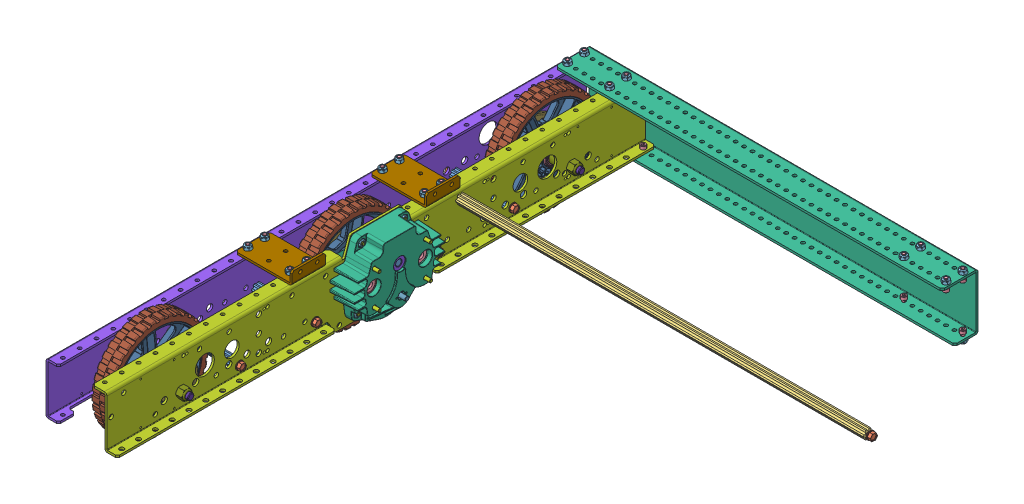
SolidWorks assembly AM14U3 Long Half, configuration Default. Lengths in mm.
Overall size (722.96 212.37 816.74).
154 component instances, 35 part files, 29 mates.
Components (placement in the parent):
- AM14U3 Long Frame Half-1: AM14U3 Long Frame Half [Default] at (0 136.1443 -762.762) size (722.38 116.33 816.74)
  - 500 Churro 3.375 in-1: 500 Churro 3.375 in [Default] at (-501.65 -66.929 448.437) x (0 0 1) z (-1 0 0) size (14.66 12.7 85.72)
  - 500 Churro 3.375 in-2: 500 Churro 3.375 in [Default] at (-501.65 -66.929 562.737) x (0 0 1) z (-1 0 0) size (14.66 12.7 85.72)
  - 500 Churro 3.375 in-3: 500 Churro 3.375 in [Default] at (-501.65 -66.929 264.287) x (0 0 1) z (-1 0 0) size (14.66 12.7 85.72)
  - 500 Churro 3.375 in-4: 500 Churro 3.375 in [Default] at (-501.65 -66.929 149.987) x (0 0 1) z (-1 0 0) size (14.66 12.7 85.72)
  - 0.25-20 x 0.75 in Thread Rolling Screw-1: 0.25-20 x 0.75 in Thread Rolling Screw [FHTS 0.25-20-G-0.75-C] at (-498.475 -66.929 562.737) x (-1 0 0) z (0 0.924225 0.381849) size (24.64 12.19 12.19)
  - 0.25-20 x 0.75 in Thread Rolling Screw-2: 0.25-20 x 0.75 in Thread Rolling Screw [FHTS 0.25-20-G-0.75-C] at (-498.475 -66.929 448.437) x (-1 0 0) z (0 0.924225 0.381849) size (24.64 12.19 12.19)
  - 0.25-20 x 0.75 in Thread Rolling Screw-3: 0.25-20 x 0.75 in Thread Rolling Screw [FHTS 0.25-20-G-0.75-C] at (-498.475 -66.929 264.287) x (-1 0 0) z (0 0.924225 0.381849) size (24.64 12.19 12.19)
  - 0.25-20 x 0.75 in Thread Rolling Screw-4: 0.25-20 x 0.75 in Thread Rolling Screw [FHTS 0.25-20-G-0.75-C] at (-498.475 -66.929 149.987) x (-1 0 0) z (0 0.924225 0.381849) size (24.64 12.19 12.19)
  - 0.25-20 x 0.75 in Thread Rolling Screw-5: 0.25-20 x 0.75 in Thread Rolling Screw [FHTS 0.25-20-G-0.75-C] at (-590.55 -66.929 562.737) size (24.64 12.19 12.19)
  - 0.25-20 x 0.75 in Thread Rolling Screw-6: 0.25-20 x 0.75 in Thread Rolling Screw [FHTS 0.25-20-G-0.75-C] at (-590.55 -66.929 448.437) size (24.64 12.19 12.19)
  - 0.25-20 x 0.75 in Thread Rolling Screw-7: 0.25-20 x 0.75 in Thread Rolling Screw [FHTS 0.25-20-G-0.75-C] at (-590.55 -66.929 149.987) size (24.64 12.19 12.19)
  - 0.25-20 x 0.75 in Thread Rolling Screw-8: 0.25-20 x 0.75 in Thread Rolling Screw [FHTS 0.25-20-G-0.75-C] at (-590.55 -66.929 264.287) size (24.64 12.19 12.19)
  - 0.25-20 x 0.75 in Thread Rolling Screw-9: 0.25-20 x 0.75 in Thread Rolling Screw [FHTS 0.25-20-G-0.75-C] at (-501.65 -15.494 229.362) size (24.64 12.19 12.19)
  - 0.25-20 x 0.75 in Thread Rolling Screw-10: 0.25-20 x 0.75 in Thread Rolling Screw [FHTS 0.25-20-G-0.75-C] at (120.65 -15.494 229.362) x (-1 0 0) z (0 -0.924225 -0.381849) size (24.64 12.19 12.19)
  - 500 Churro 24.25 in-1: 500 Churro 24.25 in [Default] at (117.475 -15.494 229.362) x (0 0 1) z (-1 0 0) size (14.66 12.7 615.95)
  - 10-32 x 0.5 in SHCS Screw-27: 10-32 x 0.5 in SHCS Screw [HX-SHCS 0.19-32x1.375x1-C] at (-577.85 -11.43 -11.938) x (0 1 0) z (0 0 1) size (17.53 7.94 7.94)
  - 10-32 x 0.5 in SHCS Screw-28: 10-32 x 0.5 in SHCS Screw [HX-SHCS 0.19-32x1.375x1-C] at (-577.85 -11.43 -37.338) x (0 1 0) z (0 0 1) size (17.53 7.94 7.94)
  - 10-32 x 0.5 in SHCS Screw-29: 10-32 x 0.5 in SHCS Screw [HX-SHCS 0.19-32x1.375x1-C] at (-514.35 -11.43 -37.338) x (0 1 0) z (0 0 1) size (17.53 7.94 7.94)
  - 10-32 x 0.5 in SHCS Screw-30: 10-32 x 0.5 in SHCS Screw [HX-SHCS 0.19-32x1.375x1-C] at (-514.35 -11.43 -11.938) x (0 1 0) z (0 0 1) size (17.53 7.94 7.94)
  - 10-32 x 0.5 in SHCS Screw-31: 10-32 x 0.5 in SHCS Screw [HX-SHCS 0.19-32x1.375x1-C] at (-488.95 -73.152 -37.338) x (0 -1 0) z (0 0 1) size (17.53 7.94 7.94)
  - 10-32 x 0.5 in SHCS Screw-32: 10-32 x 0.5 in SHCS Screw [HX-SHCS 0.19-32x1.375x1-C] at (-577.85 -73.152 -37.338) x (0 -1 0) z (0 0 1) size (17.53 7.94 7.94)
  - 10-32 x 0.5 in SHCS Screw-40: 10-32 x 0.5 in SHCS Screw [HX-SHCS 0.19-32x1.375x1-C] at (-6.35 -11.176 -11.938) x (0 1 0) z (-0.991845 0 0.127447) size (17.53 7.94 7.94)
  - 10-32 x 0.5 in SHCS Screw-41: 10-32 x 0.5 in SHCS Screw [HX-SHCS 0.19-32x1.375x1-C] at (-6.35 -11.176 -37.338) x (0 1 0) z (0.595464 0 0.803382) size (17.53 7.94 7.94)
  - 10-32 x 0.5 in SHCS Screw-42: 10-32 x 0.5 in SHCS Screw [HX-SHCS 0.19-32x1.375x1-C] at (-69.85 -11.176 -11.938) x (0 1 0) z (0.578861 0 0.815426) size (17.53 7.94 7.94)
  - 10-32 x 0.5 in SHCS Screw-43: 10-32 x 0.5 in SHCS Screw [HX-SHCS 0.19-32x1.375x1-C] at (-69.85 -11.176 -37.338) x (0 1 0) z (0.958905 0 0.283727) size (17.53 7.94 7.94)
  - 10-32 x 0.5 in SHCS Screw-44: 10-32 x 0.5 in SHCS Screw [HX-SHCS 0.19-32x1.375x1-C] at (-6.35 -73.406 -37.338) x (0 -1 0) z (-0.989362 0 -0.145473) size (17.53 7.94 7.94)
  - 10-32 x 0.5 in SHCS Screw-45: 10-32 x 0.5 in SHCS Screw [HX-SHCS 0.19-32x1.375x1-C] at (-95.25 -73.406 -37.338) x (0 -1 0) z (-0.875347 0 0.483496) size (17.53 7.94 7.94)
  - 10-32 Nylock Nut-27: 10-32 Nylock Nut [Default] at (-69.85 0 -11.938) x (1 0 0) z (0 1 0) size (10.18 11.01 7.1)
  - 10-32 Nylock Nut-28: 10-32 Nylock Nut [Default] at (-69.85 0 -37.338) x (1 0 0) z (0 1 0) size (10.18 11.01 7.1)
  - 10-32 Nylock Nut-29: 10-32 Nylock Nut [Default] at (-6.35 0 -37.338) x (1 0 0) z (0 1 0) size (10.18 11.01 7.1)
  - 10-32 Nylock Nut-30: 10-32 Nylock Nut [Default] at (-6.35 0 -11.938) x (1 0 0) z (0 1 0) size (10.18 11.01 7.1)
  - 10-32 Nylock Nut-31: 10-32 Nylock Nut [Default] at (-6.35 -84.582 -37.338) x (1 0 0) z (0 -1 0) size (10.18 11.01 7.1)
  - 10-32 Nylock Nut-32: 10-32 Nylock Nut [Default] at (-95.25 -84.582 -37.338) x (1 0 0) z (0 -1 0) size (10.18 11.01 7.1)
  - 10-32 Nylock Nut-33: 10-32 Nylock Nut [Default] at (-514.35 0 -11.938) x (1 0 0) z (0 1 0) size (10.18 11.01 7.1)
  - 10-32 Nylock Nut-34: 10-32 Nylock Nut [Default] at (-514.35 0 -37.338) x (1 0 0) z (0 1 0) size (10.18 11.01 7.1)
  - 10-32 Nylock Nut-35: 10-32 Nylock Nut [Default] at (-577.85 0 -37.338) x (1 0 0) z (0 1 0) size (10.18 11.01 7.1)
  - 10-32 Nylock Nut-36: 10-32 Nylock Nut [Default] at (-577.85 0 -11.938) x (1 0 0) z (0 1 0) size (10.18 11.01 7.1)
  - 10-32 Nylock Nut-37: 10-32 Nylock Nut [Default] at (-488.95 -84.582 -37.338) x (1 0 0) z (0 -1 0) size (10.18 11.01 7.1)
  - 10-32 Nylock Nut-38: 10-32 Nylock Nut [Default] at (-577.85 -84.582 -37.338) x (1 0 0) z (0 -1 0) size (10.18 11.01 7.1)
  - 10-32 x 0.5 in SHCS Screw-46: 10-32 x 0.5 in SHCS Screw [HX-SHCS 0.19-32x1.375x1-C] at (-577.85 -11.43 445.262) x (0 1 0) z (0 0 1) size (17.53 7.94 7.94)
  - 10-32 x 0.5 in SHCS Screw-47: 10-32 x 0.5 in SHCS Screw [HX-SHCS 0.19-32x1.375x1-C] at (-577.85 -11.43 470.662) x (0 1 0) z (0 0 1) size (17.53 7.94 7.94)
  - 10-32 x 0.5 in SHCS Screw-48: 10-32 x 0.5 in SHCS Screw [HX-SHCS 0.19-32x1.375x1-C] at (-514.35 -11.43 445.262) x (0 1 0) z (0 0 1) size (17.53 7.94 7.94)
  - 10-32 x 0.5 in SHCS Screw-49: 10-32 x 0.5 in SHCS Screw [HX-SHCS 0.19-32x1.375x1-C] at (-514.35 -11.43 470.662) x (0 1 0) z (0 0 1) size (17.53 7.94 7.94)
  - 10-32 x 0.5 in SHCS Screw-50: 10-32 x 0.5 in SHCS Screw [HX-SHCS 0.19-32x1.375x1-C] at (-577.85 -11.43 267.462) x (0 1 0) z (0 0 1) size (17.53 7.94 7.94)
  - 10-32 x 0.5 in SHCS Screw-51: 10-32 x 0.5 in SHCS Screw [HX-SHCS 0.19-32x1.375x1-C] at (-577.85 -11.43 242.062) x (0 1 0) z (0 0 1) size (17.53 7.94 7.94)
  - 10-32 x 0.5 in SHCS Screw-52: 10-32 x 0.5 in SHCS Screw [HX-SHCS 0.19-32x1.375x1-C] at (-514.35 -11.43 242.062) x (0 1 0) z (0 0 1) size (17.53 7.94 7.94)
  - 10-32 x 0.5 in SHCS Screw-53: 10-32 x 0.5 in SHCS Screw [HX-SHCS 0.19-32x1.375x1-C] at (-514.35 -11.43 267.462) x (0 1 0) z (0 0 1) size (17.53 7.94 7.94)
  - 10-32 Nylock Nut-39: 10-32 Nylock Nut [Default] at (-514.35 -0.254 267.462) x (1 0 0) z (0 1 0) size (10.18 11.01 7.1)
  - 10-32 Nylock Nut-40: 10-32 Nylock Nut [Default] at (-514.35 -0.254 242.062) x (1 0 0) z (0 1 0) size (10.18 11.01 7.1)
  - 10-32 Nylock Nut-41: 10-32 Nylock Nut [Default] at (-577.85 -0.254 267.462) x (1 0 0) z (0 1 0) size (10.18 11.01 7.1)
  - 10-32 Nylock Nut-42: 10-32 Nylock Nut [Default] at (-577.85 -0.254 242.062) x (1 0 0) z (0 1 0) size (10.18 11.01 7.1)
  - 10-32 Nylock Nut-43: 10-32 Nylock Nut [Default] at (-514.35 -0.254 470.662) x (1 0 0) z (0 1 0) size (10.18 11.01 7.1)
  - 10-32 Nylock Nut-44: 10-32 Nylock Nut [Default] at (-577.85 -0.254 470.662) x (1 0 0) z (0 1 0) size (10.18 11.01 7.1)
  - 10-32 Nylock Nut-45: 10-32 Nylock Nut [Default] at (-577.85 -0.254 445.262) x (1 0 0) z (0 1 0) size (10.18 11.01 7.1)
  - 10-32 Nylock Nut-46: 10-32 Nylock Nut [Default] at (-514.35 -0.254 445.262) x (1 0 0) z (0 1 0) size (10.18 11.01 7.1)
  - AM14U3 End Plate_Long-1: AM14U3 End Plate_Long [Default] at (-488.098 60.9785 -76.8664) x (1 0 0) z (0 -1 0) size (584.2 53.97 84.58)
  - AM14U3 Inner Plate-1: AM14U3 Inner Plate [Default] at (-501.65 -77.216 762.762) x (0 0 -1) z (0 -1 0) size (812.8 38.1 116.33)
  - AM14U3 Outer Plate-1: AM14U3 Outer Plate [DefaultSM-FLAT-PATTERN] at (-587.375 -77.216 -50.038) x (0 0 1) z (0 -1 0) size (812.8 19.05 77.72)
  - Bracket 2x3 Hole Pattern-1: Bracket 2x3 Hole Pattern [Default] at (-584.2 -3.429 496.062) size (85.72 19.05 50.8)
  - Bracket 2x3 Hole Pattern-2: Bracket 2x3 Hole Pattern [Default] at (-584.2 -3.429 292.862) size (85.72 19.05 50.8)
- Wheel HiGrip 6 in - Bearings, Pulleys, Spacers-1: Wheel HiGrip 6 in - Bearings, Pulleys, Spacers [Default] at (-576.1365 93.2036 -263.8267) x (1 0 0) z (0 -0.576171 0.817329) size (85.56 152.4 152.4)
  - Wheel HiGrip 6 in-1: Wheel HiGrip 6 in [Default] at (83.7987 67.439 110.9939) size (35.05 152.4 152.4)
    - Wheel HiGrip 6 in_Wheel-1: Wheel HiGrip 6 in_Wheel [Default] at (-52.6446 9.4231 21.378) size (35.05 132.08 132.08)
    - Wheel HiGrip 6 in_Tread-1: Wheel HiGrip 6 in_Tread [Default] at (-65.3446 9.4231 21.378) x (0 0 -1) z (1 0 0) size (152.4 152.4 25.58)
  - Half Pulley 42t 5 mm HTD-1: Half Pulley 42t 5 mm HTD [Default] at (47.6006 76.862 132.3719) x (1 0 0) z (0 -0.5 0.866025) size (13 74.23 74.23)
  - Half Pulley 42t 5 mm HTD-2: Half Pulley 42t 5 mm HTD [Default] at (64.263 76.862 132.3719) x (-1 0 0) z (0 -0.499927 0.866067) size (13 74.23 74.23)
  - Bearing 1614ZZ-1: Bearing 1614ZZ [Default] at (62.612 76.862 132.3719) x (0 -0.157148 -0.987575) z (-1 0 0) size (28.57 28.57 9.53)
  - Bearing 1614ZZ-2: Bearing 1614ZZ [Default] at (15.2791 76.862 132.3719) x (0 0 -1) z (1 0 0) size (28.57 28.57 9.53)
  - 10-24 x 1.25 in Thread Forming Screw-1: 10-24 x 1.25 in Thread Forming Screw [93882A213] at (63.247 76.8605 108.5602) x (0 0 -1) z (1 0 0) size (10.52 10.52 35.59)
  - 10-24 x 1.25 in Thread Forming Screw-2: 10-24 x 1.25 in Thread Forming Screw [93882A213] at (63.247 97.4833 120.4656) x (0 0 -1) z (1 0 0) size (10.52 10.52 35.59)
  - 10-24 x 1.25 in Thread Forming Screw-3: 10-24 x 1.25 in Thread Forming Screw [93882A213] at (63.247 56.2398 144.2799) x (0 0 -1) z (1 0 0) size (10.52 10.52 35.59)
  - 10-24 x 1.25 in Thread Forming Screw-4: 10-24 x 1.25 in Thread Forming Screw [93882A213] at (63.247 76.8625 156.1852) x (0 -0.95788 -0.287168) z (1 0 0) size (10.52 10.52 35.59)
  - 10-24 x 1.25 in Thread Forming Screw-5: 10-24 x 1.25 in Thread Forming Screw [93882A213] at (63.247 97.4843 144.2781) x (0 -0.868976 0.494854) z (1 0 0) size (10.52 10.52 35.59)
  - 10-24 x 1.25 in Thread Forming Screw-6: 10-24 x 1.25 in Thread Forming Screw [93882A213] at (63.247 56.2388 120.4674) x (0 -0.977348 -0.211637) z (1 0 0) size (10.52 10.52 35.59)
  - Spacer 0.28 in x 0.382 ID-1: Spacer 0.28 in x 0.382 ID [Default] at (74.4865 76.862 132.3719) x (0 -0.35357 0.935408) z (-1 0 0) size (13.16 13.16 7.11)
  - Spacer 0.85 in x 0.38 ID-1: Spacer 0.85 in x 0.38 ID [Default] at (-11.0734 76.862 132.3719) x (0 0 -1) z (1 0 0) size (19.05 19.05 21.59)
- Wheel HiGrip 6 in - Bearings, Pulleys, Spacers-2: Wheel HiGrip 6 in - Bearings, Pulleys, Spacers [Default] at (-512.7234 172.7479 -579.8665) x (-1 0 0) z (0 -0.924225 -0.381849) size (85.56 152.4 152.4)
  - Wheel HiGrip 6 in-1: Wheel HiGrip 6 in [Default] at (83.7987 67.439 110.9939) size (35.05 152.4 152.4)
    - Wheel HiGrip 6 in_Wheel-1: Wheel HiGrip 6 in_Wheel [Default] at (-52.6446 9.4231 21.378) size (35.05 132.08 132.08)
    - Wheel HiGrip 6 in_Tread-1: Wheel HiGrip 6 in_Tread [Default] at (-65.3446 9.4231 21.378) x (0 0 -1) z (1 0 0) size (152.4 152.4 25.58)
  - Half Pulley 42t 5 mm HTD-1: Half Pulley 42t 5 mm HTD [Default] at (47.6006 76.862 132.3719) x (1 0 0) z (0 -0.5 0.866025) size (13 74.23 74.23)
  - Half Pulley 42t 5 mm HTD-2: Half Pulley 42t 5 mm HTD [Default] at (64.263 76.862 132.3719) x (-1 0 0) z (0 -0.499927 0.866067) size (13 74.23 74.23)
  - Bearing 1614ZZ-1: Bearing 1614ZZ [Default] at (62.612 76.862 132.3719) x (0 -0.157148 -0.987575) z (-1 0 0) size (28.57 28.57 9.53)
  - Bearing 1614ZZ-2: Bearing 1614ZZ [Default] at (15.2791 76.862 132.3719) x (0 0 -1) z (1 0 0) size (28.57 28.57 9.53)
  - 10-24 x 1.25 in Thread Forming Screw-1: 10-24 x 1.25 in Thread Forming Screw [93882A213] at (63.247 76.8605 108.5602) x (0 0 -1) z (1 0 0) size (10.52 10.52 35.59)
  - 10-24 x 1.25 in Thread Forming Screw-2: 10-24 x 1.25 in Thread Forming Screw [93882A213] at (63.247 97.4833 120.4656) x (0 0 -1) z (1 0 0) size (10.52 10.52 35.59)
  - 10-24 x 1.25 in Thread Forming Screw-3: 10-24 x 1.25 in Thread Forming Screw [93882A213] at (63.247 56.2398 144.2799) x (0 0 -1) z (1 0 0) size (10.52 10.52 35.59)
  - 10-24 x 1.25 in Thread Forming Screw-4: 10-24 x 1.25 in Thread Forming Screw [93882A213] at (63.247 76.8625 156.1852) x (0 -0.95788 -0.287168) z (1 0 0) size (10.52 10.52 35.59)
  - 10-24 x 1.25 in Thread Forming Screw-5: 10-24 x 1.25 in Thread Forming Screw [93882A213] at (63.247 97.4843 144.2781) x (0 -0.868976 0.494854) z (1 0 0) size (10.52 10.52 35.59)
  - 10-24 x 1.25 in Thread Forming Screw-6: 10-24 x 1.25 in Thread Forming Screw [93882A213] at (63.247 56.2388 120.4674) x (0 -0.977348 -0.211637) z (1 0 0) size (10.52 10.52 35.59)
  - Spacer 0.28 in x 0.382 ID-1: Spacer 0.28 in x 0.382 ID [Default] at (74.4865 76.862 132.3719) x (0 -0.35357 0.935408) z (-1 0 0) size (13.16 13.16 7.11)
  - Spacer 0.85 in x 0.38 ID-1: Spacer 0.85 in x 0.38 ID [Default] at (-11.0734 76.862 132.3719) x (0 0 -1) z (1 0 0) size (19.05 19.05 21.59)
- Wheel HiGrip 6 in - Hub, Double Pulley-1: Wheel HiGrip 6 in - Hub, Double Pulley [Default] at (-512.6497 221.6536 -358.7197) x (-1 0 0) z (0 -0.978174 0.207786) size (81.42 152.4 152.4)
  - Wheel HiGrip 6 in-1: Wheel HiGrip 6 in [Default] at (83.7987 67.439 110.9939) size (35.05 152.4 152.4)
    - Wheel HiGrip 6 in_Wheel-1: Wheel HiGrip 6 in_Wheel [Default] at (-52.6446 9.4231 21.378) size (35.05 132.08 132.08)
    - Wheel HiGrip 6 in_Tread-1: Wheel HiGrip 6 in_Tread [Default] at (-65.3446 9.4231 21.378) x (0 0 -1) z (1 0 0) size (152.4 152.4 25.58)
  - Half Pulley 42t 5 mm HTD-1: Half Pulley 42t 5 mm HTD [Default] at (47.6006 76.862 132.3719) x (1 0 0) z (0 -0.5 0.866025) size (13 74.23 74.23)
  - Half Pulley 42t 5 mm HTD-2: Half Pulley 42t 5 mm HTD [Default] at (64.263 76.862 132.3719) x (-1 0 0) z (0 -0.499927 0.866067) size (13 74.23 74.23)
  - 10-24 x 1.25 in Thread Forming Screw-1: 10-24 x 1.25 in Thread Forming Screw [93882A213] at (63.247 76.8605 108.5602) x (0 0 -1) z (1 0 0) size (10.52 10.52 35.59)
  - 10-24 x 1.25 in Thread Forming Screw-2: 10-24 x 1.25 in Thread Forming Screw [93882A213] at (63.247 97.4833 120.4656) x (0 0 -1) z (1 0 0) size (10.52 10.52 35.59)
  - 10-24 x 1.25 in Thread Forming Screw-3: 10-24 x 1.25 in Thread Forming Screw [93882A213] at (63.247 56.2398 144.2799) x (0 0 -1) z (1 0 0) size (10.52 10.52 35.59)
  - 10-24 x 1.25 in Thread Forming Screw-4: 10-24 x 1.25 in Thread Forming Screw [93882A213] at (63.247 76.8625 156.1852) x (0 -0.95788 -0.287168) z (1 0 0) size (10.52 10.52 35.59)
  - 10-24 x 1.25 in Thread Forming Screw-5: 10-24 x 1.25 in Thread Forming Screw [93882A213] at (63.247 97.4843 144.2781) x (0 -0.868976 0.494854) z (1 0 0) size (10.52 10.52 35.59)
  - 10-24 x 1.25 in Thread Forming Screw-6: 10-24 x 1.25 in Thread Forming Screw [93882A213] at (63.247 56.2388 120.4674) x (0 -0.748729 -0.662876) z (1 0 0) size (10.52 10.52 35.59)
  - Half Pulley 42t 5 mm HTD-3: Half Pulley 42t 5 mm HTD [Default] at (-1.9548 76.8628 132.3714) x (1 0 0) z (0 -1 -0.000063) size (13 74.23 74.23)
  - Half Pulley 42t 5 mm HTD-4: Half Pulley 42t 5 mm HTD [Default] at (14.7076 76.8628 132.3714) x (-1 0 0) z (0 -1 0.000021) size (13 74.23 74.23)
  - Hex Hub 500 EX-1: Hex Hub 500 EX [Default] at (-8.3048 76.8628 132.3714) x (0 -0.866025 -0.5) z (0 -0.5 0.866025) size (55.37 25.4 51.33)
  - 10-24 x 1.25 in Thread Forming Screw-7: 10-24 x 1.25 in Thread Forming Screw [93882A213] at (-5.2568 97.485 120.4652) x (0 0 1) z (-1 0 0) size (10.52 10.52 35.59)
  - 10-24 x 1.25 in Thread Forming Screw-8: 10-24 x 1.25 in Thread Forming Screw [93882A213] at (-5.2568 76.8628 108.5589) x (0 0 1) z (-1 0 0) size (10.52 10.52 35.59)
  - 10-24 x 1.25 in Thread Forming Screw-9: 10-24 x 1.25 in Thread Forming Screw [93882A213] at (-5.2568 56.2406 120.4652) x (0 0 1) z (-1 0 0) size (10.52 10.52 35.59)
  - 10-24 x 1.25 in Thread Forming Screw-10: 10-24 x 1.25 in Thread Forming Screw [93882A213] at (-5.2568 97.485 144.2777) x (0 -0.99374 -0.111715) z (-1 0 0) size (10.52 10.52 35.59)
  - 10-24 x 1.25 in Thread Forming Screw-11: 10-24 x 1.25 in Thread Forming Screw [93882A213] at (-5.2568 56.2406 144.2777) x (0 -0.138911 0.990305) z (-1 0 0) size (10.52 10.52 35.59)
  - 10-24 x 1.25 in Thread Forming Screw-12: 10-24 x 1.25 in Thread Forming Screw [93882A213] at (-5.2568 76.8628 156.1839) x (0 -0.98811 -0.15375) z (-1 0 0) size (10.52 10.52 35.59)
  - Hex Spacer 0.57 in x 0.5 ID-1: Hex Spacer 0.57 in x 0.5 ID [Default] at (57.8495 76.862 132.3719) x (0 -0.866025 -0.5) z (0 -0.5 0.866025) size (28.55 14.48 28.55)
- Toughbox Mini Kit 1 - Yellow-1: Toughbox Mini Kit 1 - Yellow [Default] at (-549.0167 66.1302 -315.2992) x (0 0.001296 0.999999) z (-1 0 0) size (140.05 131.97 142.29)
  - TB Mini Small Hex Shaft-1: TB Mini Small Hex Shaft [Default] at (-128.9299 31.4042 -52.3959) x (-0.63944 -0.768841 0) z (-0.768841 0.63944 0) size (11 38.23 9.52)
  - Large Cluster Gear Hex 50t 0.375 in-1: Large Cluster Gear Hex 50t 0.375 in [Default] at (-91.0349 50.9043 -67.5597) x (-0.63944 -0.768841 0) z (0 0 -1) size (65.97 66.04 10.16)
  - Bearing FR6ZZ-1: Bearing FR6ZZ [Default] at (-96.247 60.278 -52.5991) x (-0.893862 0.448342 0) z (0 0 1) size (24.69 24.69 7.16)
  - 10-32 Nylock Nut-1: 10-32 Nylock Nut [Default] at (-129.8464 -8.0737 -56.3837) x (0.501678 0.865055 0) z (0 0 -1) size (10.18 11.01 7.1)
  - 10-32 Nylock Nut-2: 10-32 Nylock Nut [Default] at (-59.2462 80.7349 -56.3837) x (0.999999 -0.001296 0) z (0 0 -1) size (10.18 11.01 7.1)
  - 10-32 Nylock Nut-3: 10-32 Nylock Nut [Default] at (-122.7461 80.8172 -56.3837) x (0.500567 0.865698 0) z (0 0 -1) size (10.18 11.01 7.1)
  - 10-32 Nylock Nut-4: 10-32 Nylock Nut [Default] at (-52.3764 -8.1741 -56.3837) x (-0.501678 -0.865055 0) z (0 0 -1) size (10.18 11.01 7.1)
  - Washer 5-16 in-1: Washer 5-16 in [Default] at (-52.3162 38.3079 -77.7705) x (-0.418041 0.908428 0) z (0 0 -1) size (17.53 17.53 1.47)
  - Washer 5-16 in-2: Washer 5-16 in [Default] at (-52.3162 38.3079 -76.2973) x (0.897267 -0.441488 0) z (0 0 -1) size (17.53 17.53 1.47)
  - Washer 5-16 in-3: Washer 5-16 in [Default] at (-129.7861 38.4083 -77.7705) x (-0.990116 0.140253 0) z (0 0 1) size (17.53 17.53 1.47)
  - Washer 5-16 in-4: Washer 5-16 in [Default] at (-129.7861 38.4083 -79.2437) x (-0.681761 0.731575 0) z (0 0 1) size (17.53 17.53 1.47)
  - CIM Gear 14t 8 mm-1: CIM Gear 14t 8 mm [Default] at (-52.3162 38.3079 -63.5973) x (0.081921 0.996639 0) z (0 0 -1) size (20.03 20.32 12.7)
  - CIM Gear 14t 8 mm-2: CIM Gear 14t 8 mm [Default] at (-129.7861 38.4083 -63.5973) x (0.725998 0.687697 0) z (0 0 -1) size (20.03 20.32 12.7)
  - TB Mini Housing-1: TB Mini Housing [Default] at (-91.0876 10.1882 -86.3557) x (0.999999 -0.001296 0) z (0 0 1) size (139.9 118.55 41.54)
  - 10-32 x 0.625 in SHCS Screw-1: 10-32 x 0.625 in SHCS Screw [Default] at (-52.2832 63.7078 -74.4685) x (-0.564778 -0.825243 0) z (-0.825243 0.564778 0) size (7.82 20.65 7.82)
  - 10-32 x 0.625 in SHCS Screw-2: 10-32 x 0.625 in SHCS Screw [Default] at (-122.7461 80.8172 -42.5915) x (0.507484 -0.861661 0) z (-0.861661 -0.507484 0) size (7.82 20.65 7.82)
  - 10-32 x 0.625 in SHCS Screw-3: 10-32 x 0.625 in SHCS Screw [Default] at (-52.3764 -8.1741 -42.5915) x (0.507484 -0.861661 0) z (-0.861661 -0.507484 0) size (7.82 20.65 7.82)
  - 10-32 x 0.625 in SHCS Screw-4: 10-32 x 0.625 in SHCS Screw [Default] at (-129.8464 -8.0737 -42.5915) x (0.507484 -0.861661 0) z (-0.861661 -0.507484 0) size (7.82 20.65 7.82)
  - 10-32 x 0.625 in SHCS Screw-5: 10-32 x 0.625 in SHCS Screw [Default] at (-59.2462 80.7349 -42.5915) x (0.740711 -0.671824 0) z (-0.671824 -0.740711 0) size (7.82 20.65 7.82)
  - 10-32 x 0.625 in SHCS Screw-6: 10-32 x 0.625 in SHCS Screw [Default] at (-52.3491 12.9079 -74.4685) x (-0.564778 -0.825243 0) z (-0.825243 0.564778 0) size (7.82 20.65 7.82)
  - 10-32 x 0.625 in SHCS Screw-7: 10-32 x 0.625 in SHCS Screw [Default] at (-129.7532 63.8083 -74.4685) x (-0.966277 -0.257503 0) z (-0.257503 0.966277 0) size (7.82 20.65 7.82)
  - 10-32 x 0.625 in SHCS Screw-8: 10-32 x 0.625 in SHCS Screw [Default] at (-129.819 13.0083 -74.4685) x (-0.99652 0.083357 0) z (0.083357 0.99652 0) size (7.82 20.65 7.82)
  - Bearing R6ZZ-3: Bearing R6ZZ [Default] at (-91.0349 50.9043 -84.8317) x (0.958138 -0.286306 0) z (0 0 1) size (22.23 22.23 7.11)
  - Bearing R6ZZ-4: Bearing R6ZZ [Default] at (-91.0876 10.1882 -84.8317) x (-0.661529 0.74992 0) z (0 0 1) size (22.23 22.23 7.11)
  - Retaining Clip 8 mm-1: Retaining Clip 8 mm [Default] at (-129.7861 38.4083 -63.5973) x (0 0 1) z (-1 0 0) size (1.09 14.83 14.83)
  - Retaining Clip 8 mm-2: Retaining Clip 8 mm [Default] at (-52.3162 38.3079 -63.5973) x (0 0 1) z (-1 0 0) size (1.09 14.83 14.83)
  - External Klipring 0.5 in-1: External Klipring 0.5 in [Default] at (-91.0876 10.1882 -64.4355) x (0.996411 -0.084651 0) z (0 0 1) size (19.07 20.96 1.27)
  - Hex Bearing FR8ZZ-1: Hex Bearing FR8ZZ [Default] at (-91.0876 10.1882 -44.6717) x (0.206517 -0.978443 0) z (0 0 -1) size (31.12 31.12 7.93)
  - Small Cluster Gear Hex 16t 0.375 in-1: Small Cluster Gear Hex 16t 0.375 in [Default] at (-91.0349 50.9043 -67.5597) x (0 0 1) z (0.346116 -0.938192 0) size (15.19 22.57 22.57)
  - Large Output Gear Hex 48t 0.5 in-1: Large Output Gear Hex 48t 0.5 in [Default] at (-91.0876 10.1882 -63.1655) x (0 0 1) z (0.744098 0.668071 0) size (10.21 63.42 63.42)
  - TB Mini Hex Output Shaft-2: TB Mini Hex Output Shaft [Default] at (-99.4862 -30.7356 -52.3197) x (0.206517 -0.978443 0) z (-0.978443 -0.206517 0) size (14.66 142.29 12.7)
- Hex Bearing FR8ZZ-1: Hex Bearing FR8ZZ [Default] at (-593.7783 76.2003 -406.4) x (0 0.309139 -0.951017) z (1 0 0) size (31.12 31.12 7.93)
- Timing Belt HTD 15 mm_Long-1: Timing Belt HTD 15 mm_Long [Default] at (-511.8735 79.7563 -111.3496) x (0 -0.012051 -0.999927) z (0 0.999927 -0.012051) size (368.15 15 73.08)
- Timing Belt HTD 15 mm_Long-2: Timing Belt HTD 15 mm_Long [Default] at (-576.9127 76.2003 -406.4) x (0 0.012051 -0.999927) z (0 -0.999927 -0.012051) size (368.15 15 73.08) (hidden)
- 0.375-16 Nylock Nut-1: 0.375-16 Nylock Nut [91831A127] at (-498.475 79.7563 -701.4504) x (0 -1 0) z (0 0 1) size (14.29 12 16.5)
- 0.375-16 Nylock Nut-2: 0.375-16 Nylock Nut [91831A127] at (-498.475 79.7563 -111.3496) x (0 -1 0) z (0 0 1) size (14.29 12 16.5)
- 0.375-16 x 4.25 in HHS Bolt-1: 0.375-16 x 4.25 in HHS Bolt [HFBOLT 0.375-16x2.5x1-C] at (-596.7222 79.7563 -111.3496) size (114.12 16.48 14.27)
- 0.375-16 x 4.25 in HHS Bolt-2: 0.375-16 x 4.25 in HHS Bolt [HFBOLT 0.375-16x2.5x1-C] at (-596.7222 79.7563 -701.4504) size (114.12 16.48 14.27)
Mates (geometry in assembly coordinates):
- Concentric1: concentric aligned: cylinder of AM14U3 Long Frame Half-1/AM14U3 Inner Plate-1 through (-520.7 79.7563 -111.3496) axis (1 0 0) radius 4.826; cylinder of Wheel HiGrip 6 in - Bearings, Pulleys, Spacers-1/Spacer 0.28 in x 0.382 ID-1 through (-508.762 79.7563 -111.3496) axis (1 0 0) radius 6.5786
- Coincident1: coincident anti-aligned: plane of AM14U3 Long Frame Half-1/AM14U3 Inner Plate-1 through (-501.65 128.7783 0) normal (-1 0 0); plane of Wheel HiGrip 6 in - Bearings, Pulleys, Spacers-1/Spacer 0.28 in x 0.382 ID-1 through (-501.65 79.7563 -111.3496) normal (1 0 0)
- Concentric2: concentric anti-aligned: cylinder of AM14U3 Long Frame Half-1/AM14U3 Inner Plate-1 through (-520.7 79.7563 -701.4504) axis (1 0 0) radius 4.826; cylinder of Wheel HiGrip 6 in - Bearings, Pulleys, Spacers-2/Spacer 0.28 in x 0.382 ID-1 through (-580.0979 79.7563 -701.4504) axis (-1 0 0) radius 6.5786
- Coincident2: coincident anti-aligned: plane of AM14U3 Long Frame Half-1/AM14U3 Inner Plate-1 through (-501.65 128.7783 0) normal (-1 0 0); plane of Wheel HiGrip 6 in - Bearings, Pulleys, Spacers-2/Spacer 0.85 in x 0.38 ID-1 through (-501.65 79.7563 -701.4504) normal (1 0 0)
- Concentric3: concentric anti-aligned: cylinder of AM14U3 Long Frame Half-1/AM14U3 Inner Plate-1 through (-501.65 76.2003 -406.4) axis (1 0 0) radius 14.2875; cylinder of Toughbox Mini Kit 1 - Yellow-1/Hex Bearing FR8ZZ-1 through (-496.4176 76.2003 -406.4) axis (-1 0 0) radius 14.2875
- Parallel1: parallel: plane of AM14U3 Long Frame Half-1/AM14U3 Inner Plate-1 through (-498.475 156.2103 -454.025) normal (0 1 0); line of Toughbox Mini Kit 1 - Yellow-1/TB Mini Housing-1 through (-497.9493 155.7675 -438.15) axis (0 0 1)
- Coincident4: coincident anti-aligned: plane of AM14U3 Long Frame Half-1/AM14U3 Inner Plate-1 through (-498.475 128.7783 0) normal (1 0 0); plane of Toughbox Mini Kit 1 - Yellow-1/TB Mini Housing-1 through (-498.475 76.2003 -406.4) normal (-1 0 0)
- Concentric41: concentric aligned: cylinder of AM14U3 Long Frame Half-1/AM14U3 Outer Plate-1 through (-587.375 76.2003 -406.4) axis (-1 0 0) radius 14.2875; cylinder of Hex Bearing FR8ZZ-1 through (-585.851 76.2003 -406.4) axis (-1 0 0) radius 13.97
- Coincident51: coincident anti-aligned: plane of AM14U3 Long Frame Half-1/AM14U3 Outer Plate-1 through (-587.375 128.7783 -812.8) normal (1 0 0); plane of Hex Bearing FR8ZZ-1 through (-587.375 80.5189 -419.6857) normal (-1 0 0)
- Coincident6: coincident anti-aligned: plane of Toughbox Mini Kit 1 - Yellow-1/TB Mini Hex Output Shaft-2 through (-471.297 83.3726 -407.9236) normal (0 0.743231 -0.669035); plane of Hex Bearing FR8ZZ-1 through (-585.851 83.3726 -407.9236) normal (0 -0.743231 0.669035)
- Concentric5: concentric aligned: cylinder of Wheel HiGrip 6 in - Hub, Double Pulley-1/Hex Hub 500 EX-1 through (-478.2153 76.2003 -406.4) axis (-1 0 0) radius 9.2382; cylinder of Toughbox Mini Kit 1 - Yellow-1/Hex Bearing FR8ZZ-1 through (-496.4176 76.2003 -406.4) axis (-1 0 0) radius 14.2875
- Parallel2: parallel aligned: plane of Wheel HiGrip 6 in - Hub, Double Pulley-1/Hex Hub 500 EX-1 through (-504.3449 71.2849 -411.8605) normal (0 0.951017 0.309139); plane of Toughbox Mini Kit 1 - Yellow-1/TB Mini Hex Output Shaft-2 through (-471.297 81.1059 -400.9504) normal (0 0.951017 0.309139)
- Coincident8: coincident anti-aligned: plane of Wheel HiGrip 6 in - Hub, Double Pulley-1/Hex Hub 500 EX-1 through (-504.3449 76.2003 -406.4) normal (1 0 0); plane of Toughbox Mini Kit 1 - Yellow-1/Hex Bearing FR8ZZ-1 through (-504.3449 76.2003 -406.4) normal (-1 0 0)
- Concentric6: concentric anti-aligned: cylinder of Wheel HiGrip 6 in - Bearings, Pulleys, Spacers-1/Spacer 0.85 in x 0.38 ID-1 through (-565.6199 79.7563 -111.3496) axis (-1 0 0) radius 9.525; cylinder of Timing Belt HTD 15 mm_Long-1 through (-526.8735 79.7563 -111.3496) axis (1 0 0) radius 35.0139
- Concentric7: concentric anti-aligned: cylinder of Hex Bearing FR8ZZ-1 through (-585.851 76.2003 -406.4) axis (-1 0 0) radius 14.2875; cylinder of Timing Belt HTD 15 mm_Long-1 through (-526.8735 76.2003 -406.4) axis (1 0 0) radius 35.0139
- Coincident9: coincident anti-aligned: plane of Wheel HiGrip 6 in - Bearings, Pulleys, Spacers-1/Half Pulley 42t 5 mm HTD-2 through (-511.8735 79.7563 -111.3496) normal (-1 0 0); plane of Timing Belt HTD 15 mm_Long-1 through (-511.8735 79.7563 -111.3496) normal (1 0 0)
- Concentric8: concentric anti-aligned: cylinder of Wheel HiGrip 6 in - Bearings, Pulleys, Spacers-2/Spacer 0.85 in x 0.38 ID-1 through (-523.24 79.7563 -701.4504) axis (1 0 0) radius 9.525; cylinder of Timing Belt HTD 15 mm_Long-2 through (-561.9127 79.7563 -701.4504) axis (-1 0 0) radius 35.0139
- Concentric9: concentric anti-aligned: cylinder of Hex Bearing FR8ZZ-1 through (-585.851 76.2003 -406.4) axis (-1 0 0) radius 14.2875; circle of Timing Belt HTD 15 mm_Long-2
- Coincident10: coincident anti-aligned: plane of Wheel HiGrip 6 in - Hub, Double Pulley-1/Half Pulley 42t 5 mm HTD-2 through (-576.9127 76.2 -406.3992) normal (1 0 0); plane of Timing Belt HTD 15 mm_Long-2 through (-576.9127 76.2003 -406.4) normal (-1 0 0)
- Coincident13: coincident anti-aligned: plane of AM14U3 Long Frame Half-1/AM14U3 Inner Plate-1 through (-498.475 128.7783 0) normal (1 0 0); plane of 0.375-16 Nylock Nut-2 through (-498.475 86.9 -123.723) normal (-1 0 0)
- Coincident14: coincident anti-aligned: plane of AM14U3 Long Frame Half-1/AM14U3 Inner Plate-1 through (-498.475 128.7783 0) normal (1 0 0); plane of 0.375-16 Nylock Nut-1 through (-498.475 86.9 -713.8237) normal (-1 0 0)
- Coincident125: coincident aligned: plane of AM14U3 Long Frame Half-1/AM14U3 Inner Plate-1 through (-501.65 132.7153 0) normal (0 0 1); plane of assembly through (0 0 0) normal (0 0 1)
- Coincident126: coincident aligned: plane of AM14U3 Long Frame Half-1/AM14U3 End Plate_Long-1 through (0 54.7373 -813.562) normal (1 0 0); plane of assembly through (0 0 0) normal (1 0 0)
- Parallel3: parallel anti-aligned: plane of AM14U3 Long Frame Half-1/AM14U3 Inner Plate-1 through (-498.475 54.9913 -812.8) normal (0 -1 0); plane of assembly through (0 0 0) normal (0 1 0)
- Tangent1: tangent: circle of Wheel HiGrip 6 in - Hub, Double Pulley-1/Wheel HiGrip 6 in-1/Wheel HiGrip 6 in_Tread-1; plane of assembly through (0 0 0) normal (0 1 0)
- Concentric112: concentric aligned: cylinder of AM14U3 Long Frame Half-1/AM14U3 Outer Plate-1 through (-479.424 79.7563 -111.3496) axis (-1 0 0) radius 4.826; cylinder of 0.375-16 x 4.25 in HHS Bolt-1 through (-596.7222 79.7563 -111.3496) axis (-1 0 0) radius 4.7625
- Coincident127: coincident anti-aligned: plane of AM14U3 Long Frame Half-1/AM14U3 Outer Plate-1 through (-590.55 128.7783 -812.8) normal (-1 0 0); plane of 0.375-16 x 4.25 in HHS Bolt-1 through (-590.55 87.9978 -111.3496) normal (1 0 0)
- Concentric1131: concentric aligned: cylinder of AM14U3 Long Frame Half-1/AM14U3 Outer Plate-1 through (-479.424 79.7563 -701.4504) axis (-1 0 0) radius 4.826; cylinder of 0.375-16 x 4.25 in HHS Bolt-2 through (-596.7222 79.7563 -701.4504) axis (-1 0 0) radius 7.1374
- Coincident1281: coincident anti-aligned: plane of AM14U3 Long Frame Half-1/AM14U3 Outer Plate-1 through (-590.55 128.7783 -812.8) normal (-1 0 0); plane of 0.375-16 x 4.25 in HHS Bolt-2 through (-590.55 87.9978 -701.4504) normal (1 0 0)
